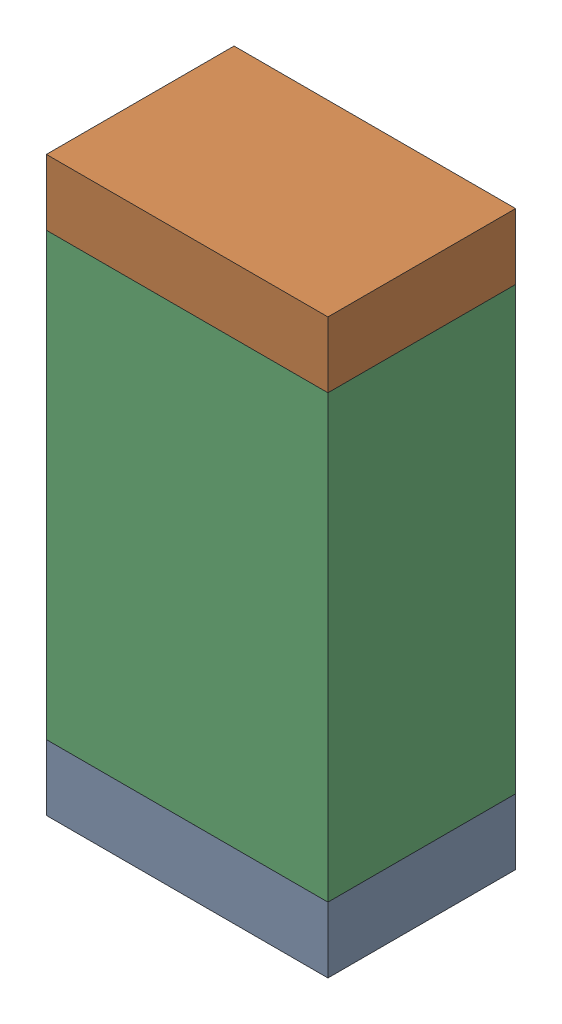
SolidWorks assembly C6, configuration Default. Lengths in mm.
Overall size (0.76 1.55 0.51).
6 component instances, 2 part files, 0 mates.
Components (placement in the parent):
- 822501776-1: 822501776 [Default] at (36.9777 2.0465 0) size (0.76 0.18 0.51)
  - Extruded_3-1: Extruded_3 [Default] at origin size (0.76 0.18 0.51)
- 822501776-2: 822501776 [Default] at (36.9777 3.4181 0) size (0.76 0.18 0.51)
  - Extruded_3-1: Extruded_3 [Default] at origin size (0.76 0.18 0.51)
- 822501912-1: 822501912 [Default] at (36.9777 2.7323 0) size (0.76 1.19 0.51)
  - Extruded_4-1: Extruded_4 [Default] at origin size (0.76 1.19 0.51)
